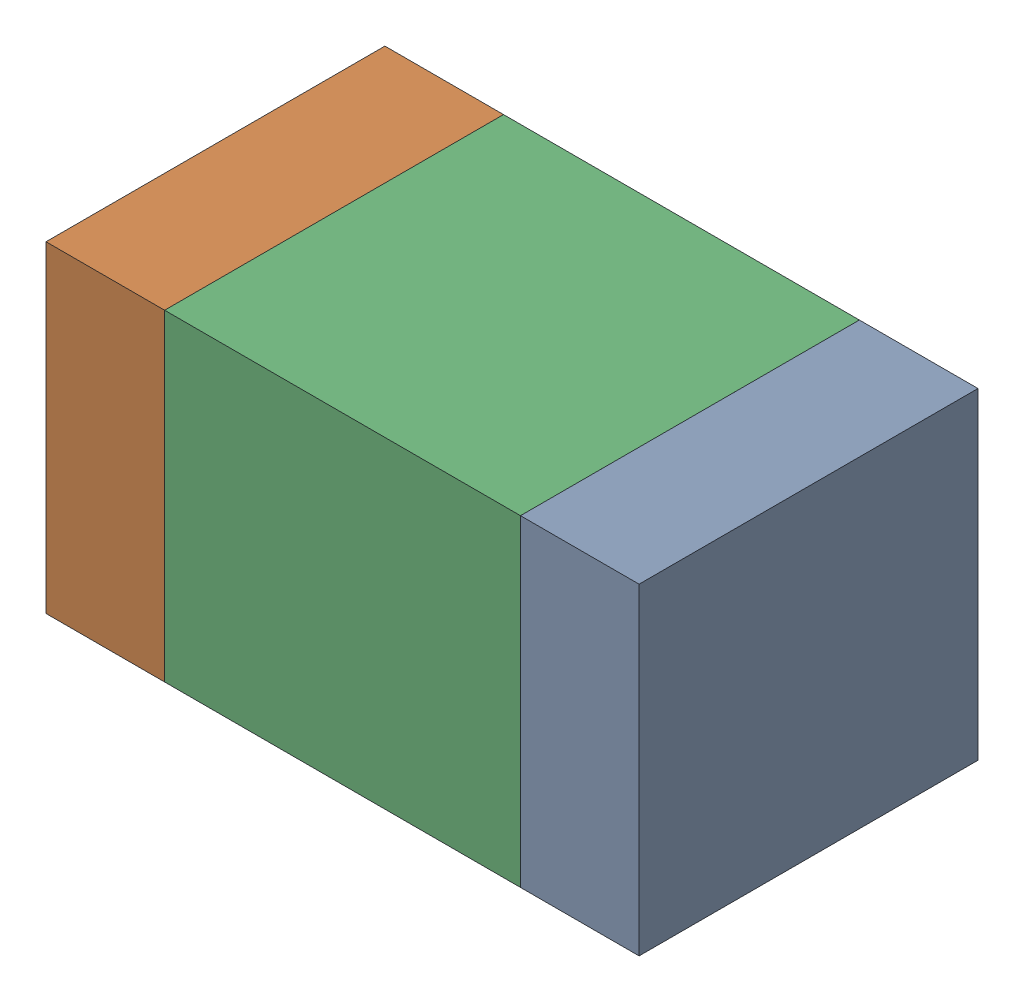
SolidWorks assembly C432PCB, configuration Default. Lengths in mm.
Overall size (1.75 0.95 1).
6 component instances, 2 part files, 0 mates.
Components (placement in the parent):
- 761616248-1: 761616248 [Default] at (123.2 90 -2.6638) size (0.35 0.95 1)
  - Extruded_15-1: Extruded_15 [Default] at origin size (0.35 0.95 1)
- 761616248-2: 761616248 [Default] at (121.8 90 -2.6638) size (0.35 0.95 1)
  - Extruded_15-1: Extruded_15 [Default] at origin size (0.35 0.95 1)
- 761616112-1: 761616112 [Default] at (122.5 90 -2.6638) size (1.05 0.95 1)
  - Extruded_14-1: Extruded_14 [Default] at origin size (1.05 0.95 1)
